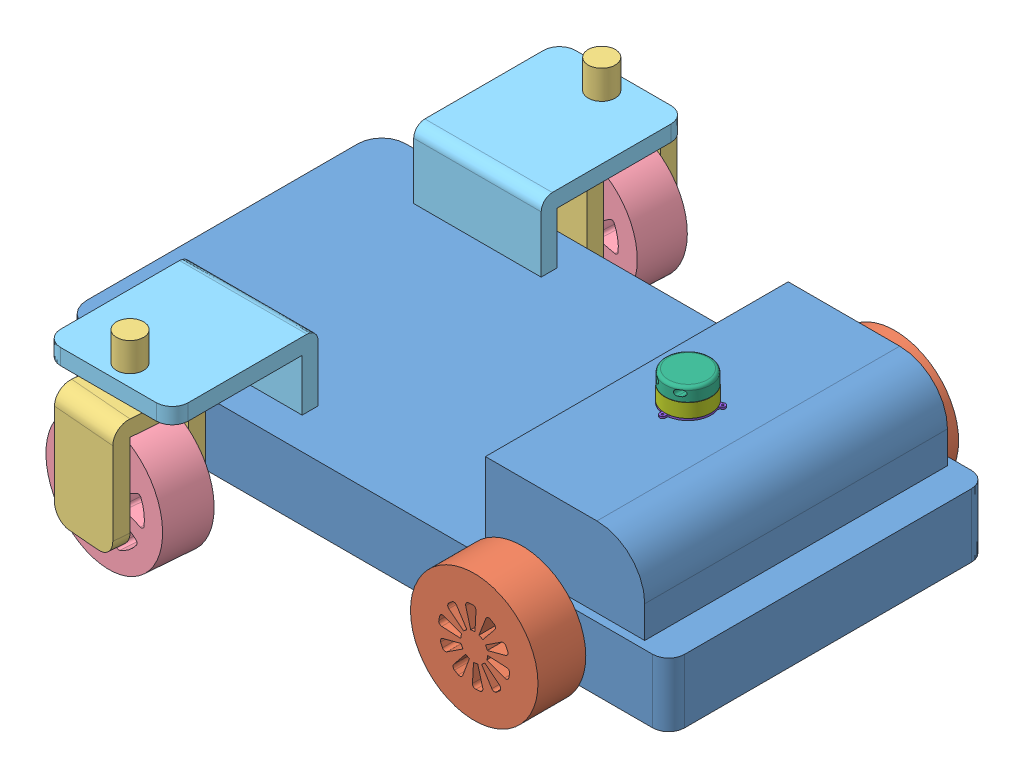
SolidWorks assembly Robot Assembly, configuration Default. Lengths in mm.
Overall size (965.2 367.65 895.3).
14 component instances, 8 part files, 20 mates.
Components (placement in the parent):
- chassis-1: chassis [Default] at (354.7404 495.1785 715.0711) size (965.2 228.6 508)
- wheel_back-1: wheel_back [Default] at (608.7404 545.9785 1050.3511) x (0.836737 0.547605 0) z (-0.547605 0.836737 0) size (203.2 152.4 203.2)
- wheel_back-2: wheel_back [Default] at (608.7404 545.9785 379.7911) x (-0.948762 0.31599 0) z (0.31599 0.948762 0) size (203.2 152.4 203.2)
- wheel_mount-1: wheel_mount [Default] at (151.7739 524.8153 335.5753) x (-0.048494 0 0.998823) z (0 -1 0) size (137.16 101.6 259.08)
- wheel_front-1: wheel_front [Default] at (102.588 542.1685 301.0959) x (-0.344226 0.938738 -0.016712) z (0.937634 0.344631 0.045523) size (203.2 76.2 203.2)
- chassis_to_wheel_mount-1: chassis_to_wheel_mount [Default] at (103.2594 596.4112 537.2711) x (-1 0 0) z (0 -1 0) size (203.2 232.41 209.55)
- chassis_to_wheel_mount-2: chassis_to_wheel_mount [Default] at (98.2214 596.4112 892.8711) x (1 0 0) z (0 -1 0) size (203.2 232.41 209.55)
- wheel_front-2: wheel_front [Default] at (97.6314 542.1685 1128.964) x (-0.84464 0.530849 -0.069155) z (-0.529079 -0.847466 -0.043318) size (203.2 76.2 203.2)
- wheel_mount-2: wheel_mount [Default] at (49.6164 524.8153 1092.8719) x (0.081602 0 -0.996665) z (0 -1 0) size (137.16 101.6 259.08)
- YDLidar G2.step-1: YDLidar G2.step [Default] at (618.4888 623.7785 719.3488) x (1 0 0) z (0 1 0) size (79.15 88.94 46)
  - Lidar Unit.step-1: Lidar Unit.step [Default] at origin size (73.7 80.79 43.05)
    - Scanner.step-1: Scanner.step [Default] at (0 0 38.5) size (72.74 72.74 21)
    - Base (1).step-1: Base (1).step [Default] at (0 0 38) size (73.7 80.79 21.55)
  - Mounting Plate.step-1: Mounting Plate.step [Default] at (0 0 38) size (79.15 81.85 3)
Mates (geometry in assembly coordinates):
- Distance1: distance = 5.08 mm anti-aligned: plane of wheel_back-1 through (608.7404 545.9785 974.1511) normal (0 0 -1); plane of chassis-1 through (-127.8596 596.7785 969.0711) normal (0 0 1)
- Distance2: distance = 5.08 mm anti-aligned: plane of chassis-1 through (-127.8596 596.7785 461.0711) normal (0 0 -1); plane of wheel_back-2 through (608.7404 545.9785 455.9911) normal (0 0 1)
- Concentric4: concentric anti-aligned: cylinder of wheel_mount-1 through (97.4146 542.1685 407.6524) axis (0.048494 0 -0.998823) radius 21.59; cylinder of wheel_front-1 through (102.588 542.1685 301.0959) axis (-0.048494 0 0.998823) radius 21.59
- Distance3: distance = 5.08 mm anti-aligned: plane of wheel_front-1 through (102.588 542.1685 301.0959) normal (0.048494 0 -0.998823); plane of wheel_mount-1 through (52.0941 648.8485 293.5584) normal (-0.048494 0 0.998823)
- Concentric5: concentric aligned: cylinder of chassis-1 through (608.7404 545.9785 461.0711) axis (0 0 1) radius 21.59; cylinder of wheel_back-1 through (608.7404 545.9785 974.1511) axis (0 0 1) radius 21.59
- Concentric6: concentric anti-aligned: cylinder of chassis-1 through (608.7404 545.9785 461.0711) axis (0 0 1) radius 21.59; cylinder of wheel_back-2 through (608.7404 545.9785 455.9911) axis (0 0 -1) radius 21.59
- Coincident7: coincident anti-aligned: plane of chassis-1 through (-0.8596 495.1775 511.8711) normal (0 0 1); plane of chassis_to_wheel_mount-1 through (103.2594 596.4112 511.8711) normal (0 0 -1)
- Coincident8: coincident aligned: plane of chassis-1 through (354.7404 495.1785 715.0711) normal (0 -1 0); plane of chassis_to_wheel_mount-1 through (202.3404 495.1785 511.8711) normal (0 -1 0)
- Coincident9: coincident anti-aligned: plane of chassis-1 through (202.3404 495.1775 537.2711) normal (-1 0 0); plane of chassis_to_wheel_mount-1 through (202.3404 704.7285 511.8711) normal (1 0 0)
- Distance4: distance = 5.08 mm anti-aligned: plane of wheel_mount-1 through (53.3259 674.2485 268.1883) normal (0 1 0); plane of chassis_to_wheel_mount-1 through (202.3404 679.3285 304.8611) normal (0 -1 0)
- Concentric8: concentric anti-aligned: cylinder of wheel_mount-1 through (100.7404 750.4485 339.1511) axis (0 -1 0) radius 21.59; cylinder of chassis_to_wheel_mount-1 through (100.7404 495.1775 339.1511) axis (0 1 0) radius 21.59
- Concentric9: concentric anti-aligned: cylinder of wheel_front-2 through (97.6314 542.1685 1128.964) axis (0.081602 0 -0.996665) radius 21.59; cylinder of wheel_mount-2 through (106.3368 542.1685 1022.6378) axis (-0.081602 0 0.996665) radius 21.59
- Distance5: distance = 5.08 mm anti-aligned: plane of wheel_front-2 through (103.8494 542.1685 1053.0182) normal (0.081602 0 -0.996665); plane of wheel_mount-2 through (154.8946 648.8485 1052.1005) normal (-0.081602 0 0.996665)
- Distance6: distance = 5.08 mm anti-aligned: plane of wheel_mount-2 through (145.7747 674.2485 1163.4878) normal (0 1 0); plane of chassis_to_wheel_mount-2 through (-0.8596 679.3285 1125.2811) normal (0 -1 0)
- Concentric10: concentric anti-aligned: cylinder of chassis_to_wheel_mount-2 through (100.7404 495.1775 1090.9911) axis (0 1 0) radius 21.59; cylinder of wheel_mount-2 through (100.7404 750.4485 1090.9911) axis (0 -1 0) radius 21.59
- Coincident12: coincident anti-aligned: plane of chassis-1 through (-0.8596 495.1775 918.2711) normal (0 0 -1); plane of chassis_to_wheel_mount-2 through (98.2214 596.4112 918.2711) normal (0 0 1)
- Coincident13: coincident anti-aligned: plane of chassis-1 through (-0.8596 495.1775 892.8711) normal (1 0 0); plane of chassis_to_wheel_mount-2 through (-0.8596 704.7285 918.2711) normal (-1 0 0)
- Coincident14: coincident aligned: plane of chassis-1 through (354.7404 495.1785 715.0711) normal (0 -1 0); plane of chassis_to_wheel_mount-2 through (-0.8596 495.1785 918.2711) normal (0 -1 0)
- Coincident15: coincident anti-aligned: plane of chassis-1 through (354.7404 723.7785 715.0711) normal (0 1 0); plane of YDLidar G2.step-1/Mounting Plate.step-1 through (618.4452 723.7785 718.4897) normal (0 -1 0)
- Distance7: distance = 205.232 mm: line of chassis-1 through (532.6232 723.7785 956.3711) axis (1 0 0); moEndPointRef_w of YDLidar G2.step-1/Lidar Unit.step-1/Scanner.step-1
